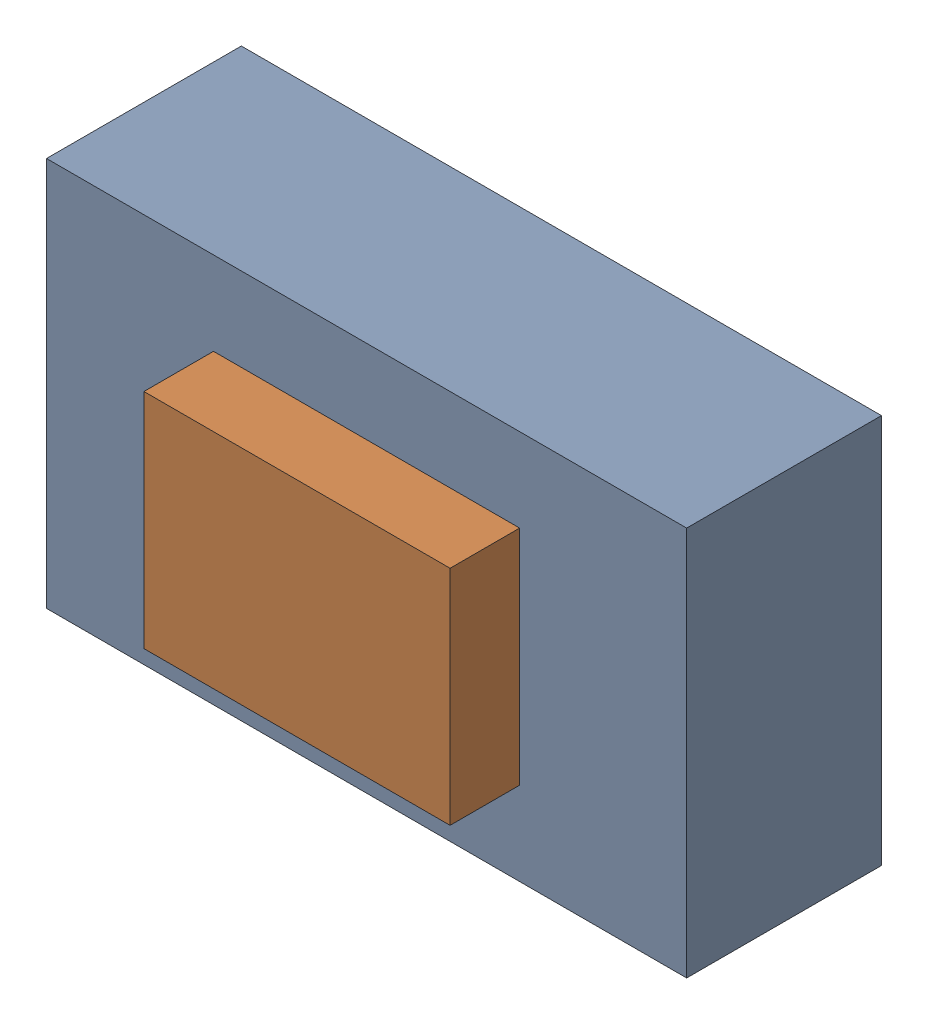
SolidWorks assembly SW2, configuration Default. Lengths in mm.
Overall size (4.6 2.8 1.9).
4 component instances, 2 part files, 0 mates.
Components (placement in the parent):
- 870942880-1: 870942880 [Default] at (53.0853 2.8427 0) size (4.6 2.8 1.4)
  - Extruded_21-1: Extruded_21 [Default] at origin size (4.6 2.8 1.4)
- 870943040-1: 870943040 [Default] at (53.0852 2.8426 1.4) size (2.2 1.6 0.5)
  - Extruded_22-1: Extruded_22 [Default] at origin size (2.2 1.6 0.5)
